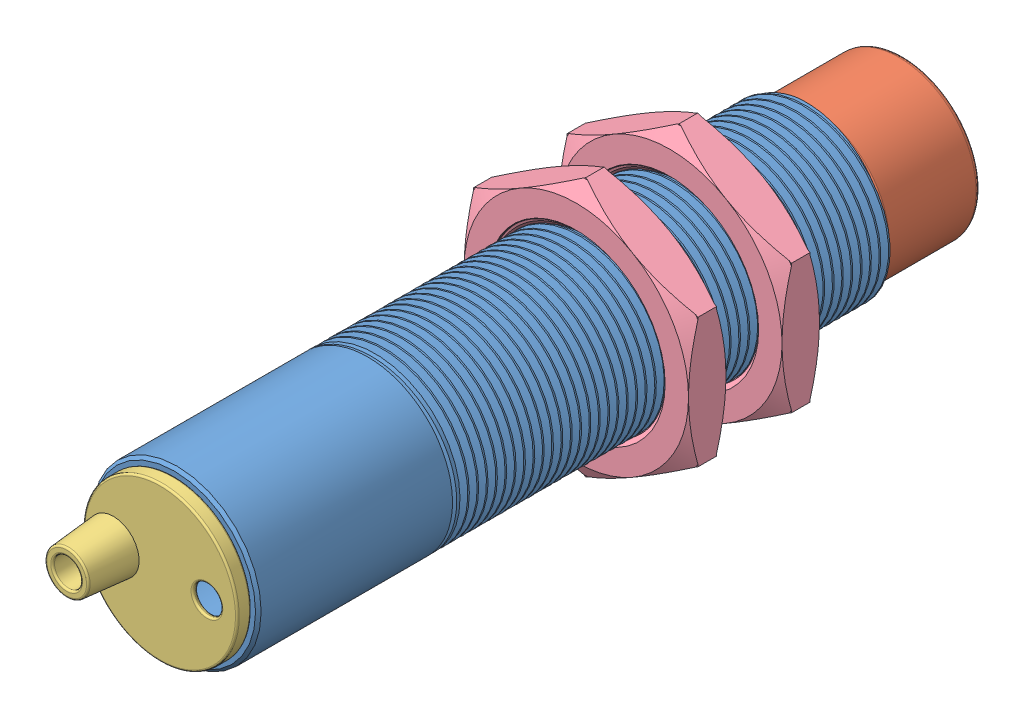
SolidWorks assembly LJC12A3-H-Z-BYX, configuration Default. Lengths in mm.
Overall size (24 27.71 84.5).
5 component instances, 4 part files, 8 mates.
Components (placement in the parent):
- LJC12A3-H-Z-BYX-1-1: LJC12A3-H-Z-BYX-1 [Default] at (0.8756 15.1692 -10.7678) size (19.52 19.04 68.65)
- LJC12A3-H-Z-BYX-2-2: LJC12A3-H-Z-BYX-2 [Default] at (0.8756 15.1692 -20.7678) x (1 0 0) z (0 1 0) size (16.5 12 16.5)
- LJC12A3-H-Z-BYX-3-1: LJC12A3-H-Z-BYX-3 [Default] at (0.8756 15.1692 58.7322) x (1 0 0) z (0 -1 0) size (16.5 8 16.5)
- LJC12A3-H-Z-BYX-4-1: LJC12A3-H-Z-BYX-4 [Default] at (0.8756 15.1692 0.2322) size (24 27.71 6)
- LJC12A3-H-Z-BYX-4-2: LJC12A3-H-Z-BYX-4 [Default] at (0.8756 15.1692 10.2322) size (24 27.71 6)
Mates (geometry in assembly coordinates):
- Coincident1: coincident anti-aligned: plane of LJC12A3-H-Z-BYX-1-1 through (0.8756 15.1692 -10.7678) normal (0 0 -1); plane of LJC12A3-H-Z-BYX-2-2 through (0.8756 22.6692 -10.7678) normal (0 0 1)
- Concentric1: concentric aligned: cylinder of LJC12A3-H-Z-BYX-1-1 through (0.8756 15.1692 57.2322) axis (0 0 -1) radius 7.5; cylinder of LJC12A3-H-Z-BYX-2-2 through (0.8756 15.1692 -20.7678) axis (0 0 -1) radius 7.5
- Concentric2: concentric anti-aligned: cylinder of LJC12A3-H-Z-BYX-1-1 through (0.8756 15.1692 57.2322) axis (0 0 -1) radius 7.5; cylinder of LJC12A3-H-Z-BYX-3-1 through (0.8756 15.1692 58.7322) axis (0 0 1) radius 7.5
- Coincident2: coincident anti-aligned: plane of LJC12A3-H-Z-BYX-1-1 through (0.8756 15.1692 57.2322) normal (0 0 1); plane of LJC12A3-H-Z-BYX-3-1 through (0.8756 6.9192 57.2322) normal (0 0 -1)
- Concentric3: concentric aligned: cylinder of LJC12A3-H-Z-BYX-1-1 through (0.8756 15.1692 57.2322) axis (0 0 -1) radius 9; circle of LJC12A3-H-Z-BYX-4-1
- Distance1: distance = 11 mm aligned: plane of LJC12A3-H-Z-BYX-1-1 through (0.8756 15.1692 -10.7678) normal (0 0 -1); plane of LJC12A3-H-Z-BYX-4-1 through (0.8756 1.3128 0.2322) normal (0 0 -1)
- Concentric6: concentric anti-aligned: cylinder of LJC12A3-H-Z-BYX-1-1 through (0.8756 15.1692 57.2322) axis (0 0 -1) radius 9; circle of LJC12A3-H-Z-BYX-4-2
- Distancia1: distance = 6 mm anti-aligned: plane of LJC12A3-H-Z-BYX-4-2 through (0.8756 1.3128 10.2322) normal (0 0 -1); plane of LJC12A3-H-Z-BYX-4-1 through (0.8756 1.3128 4.2322) normal (0 0 1)
